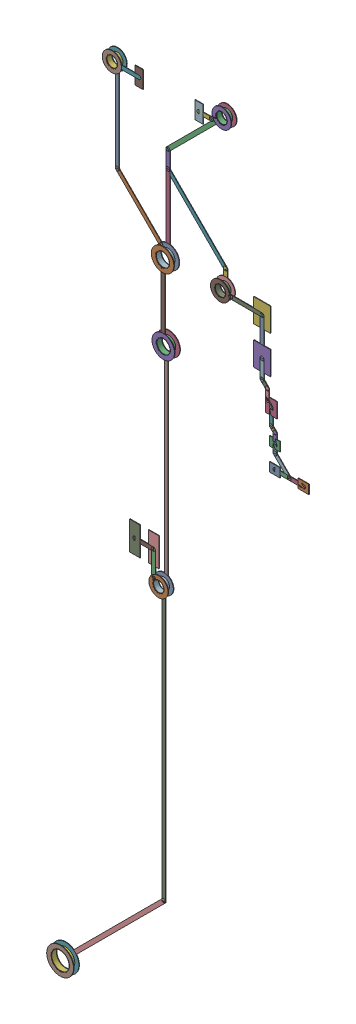
SolidWorks assembly 3V3, configuration Predeterminado. Lengths in mm.
Overall size (17.43 55.45 0.39).
184 component instances, 51 part files, 0 mates.
Components (placement in the parent):
- Track (17.2mm,51.761mm)(17.2mm,58.1mm) on Bottom Layer-1: Track (17.2mm,51.761mm)(17.2mm,58.1mm) on Bottom Layer [Predeterminado] at origin size (0.25 6.13 0.04)
  - Track (17.2mm,51.761mm)(17.2mm,58.1mm) on Bottom Layer-1-1: Track (17.2mm,51.761mm)(17.2mm,58.1mm) on Bottom Layer-1 [Predeterminado] at (-68.317 -44.187 -0.4013) size (0.25 6.13 0.04)
    - Track (17.2mm,51.761mm)(17.2mm,58.1mm) on Bottom Layer-Part-1-1: Track (17.2mm,51.761mm)(17.2mm,58.1mm) on Bottom Layer-Part-1 [Predeterminado] at origin size (0.25 6.13 0.04)
- Track (17.2mm,51.761mm)(20.574mm,48.387mm) on Bottom Layer-1: Track (17.2mm,51.761mm)(20.574mm,48.387mm) on Bottom Layer [Predeterminado] at origin size (3.29 3.29 0.04)
  - Track (17.2mm,51.761mm)(20.574mm,48.387mm) on Bottom Layer-1-1: Track (17.2mm,51.761mm)(20.574mm,48.387mm) on Bottom Layer-1 [Predeterminado] at (-68.317 -44.187 -0.4013) size (3.29 3.29 0.04)
    - Track (17.2mm,51.761mm)(20.574mm,48.387mm) on Bottom Layer-Part-1-1: Track (17.2mm,51.761mm)(20.574mm,48.387mm) on Bottom Layer-Part-1 [Predeterminado] at origin size (3.29 3.29 0.04)
- Track (20.574mm,54.574mm)(24.5mm,58.5mm) on Bottom Layer-1: Track (20.574mm,54.574mm)(24.5mm,58.5mm) on Bottom Layer [Predeterminado] at origin size (3.91 3.91 0.04)
  - Track (20.574mm,54.574mm)(24.5mm,58.5mm) on Bottom Layer-1-1: Track (20.574mm,54.574mm)(24.5mm,58.5mm) on Bottom Layer-1 [Predeterminado] at (-68.317 -44.187 -0.4013) size (3.91 3.91 0.04)
    - Track (20.574mm,54.574mm)(24.5mm,58.5mm) on Bottom Layer-Part-1-1: Track (20.574mm,54.574mm)(24.5mm,58.5mm) on Bottom Layer-Part-1 [Predeterminado] at origin size (3.91 3.91 0.04)
- Track (20.574mm,48.387mm)(20.574mm,53.426mm) on Bottom Layer-1: Track (20.574mm,48.387mm)(20.574mm,53.426mm) on Bottom Layer [Predeterminado] at origin size (0.25 4.73 0.04)
  - Track (20.574mm,48.387mm)(20.574mm,53.426mm) on Bottom Layer-1-1: Track (20.574mm,48.387mm)(20.574mm,53.426mm) on Bottom Layer-1 [Predeterminado] at (-68.317 -44.187 -0.4013) size (0.25 4.73 0.04)
    - Track (20.574mm,48.387mm)(20.574mm,53.426mm) on Bottom Layer-Part-1-1: Track (20.574mm,48.387mm)(20.574mm,53.426mm) on Bottom Layer-Part-1 [Predeterminado] at origin size (0.25 4.73 0.04)
- Track (20.574mm,53.426mm)(20.574mm,54.574mm) on Bottom Layer-1: Track (20.574mm,53.426mm)(20.574mm,54.574mm) on Bottom Layer [Predeterminado] at origin size (0.25 1.4 0.04)
  - Track (20.574mm,53.426mm)(20.574mm,54.574mm) on Bottom Layer-1-1: Track (20.574mm,53.426mm)(20.574mm,54.574mm) on Bottom Layer-1 [Predeterminado] at (-68.317 -44.187 -0.4013) size (0.25 1.4 0.04)
    - Track (20.574mm,53.426mm)(20.574mm,54.574mm) on Bottom Layer-Part-1-1: Track (20.574mm,53.426mm)(20.574mm,54.574mm) on Bottom Layer-Part-1 [Predeterminado] at origin size (0.25 1.4 0.04)
- Track (24.4mm,48.5mm)(24.4mm,49.6mm) on Bottom Layer-1: Track (24.4mm,48.5mm)(24.4mm,49.6mm) on Bottom Layer [Predeterminado] at origin size (0.25 0.89 0.04)
  - Track (24.4mm,48.5mm)(24.4mm,49.6mm) on Bottom Layer-1-1: Track (24.4mm,48.5mm)(24.4mm,49.6mm) on Bottom Layer-1 [Predeterminado] at (-68.317 -44.187 -0.4013) size (0.25 0.89 0.04)
    - Track (24.4mm,48.5mm)(24.4mm,49.6mm) on Bottom Layer-Part-1-1: Track (24.4mm,48.5mm)(24.4mm,49.6mm) on Bottom Layer-Part-1 [Predeterminado] at origin size (0.25 0.89 0.04)
- Track (20.574mm,53.426mm)(24.4mm,49.6mm) on Bottom Layer-1: Track (20.574mm,53.426mm)(24.4mm,49.6mm) on Bottom Layer [Predeterminado] at origin size (4.08 4.08 0.04)
  - Track (20.574mm,53.426mm)(24.4mm,49.6mm) on Bottom Layer-1-1: Track (20.574mm,53.426mm)(24.4mm,49.6mm) on Bottom Layer-1 [Predeterminado] at (-68.317 -44.187 -0.4013) size (4.08 4.08 0.04)
    - Track (20.574mm,53.426mm)(24.4mm,49.6mm) on Bottom Layer-Part-1-1: Track (20.574mm,53.426mm)(24.4mm,49.6mm) on Bottom Layer-Part-1 [Predeterminado] at origin size (4.08 4.08 0.04)
- Track (20.46mm,29.56mm)(20.46mm,43.24mm) on Bottom Layer-1: Track (20.46mm,29.56mm)(20.46mm,43.24mm) on Bottom Layer [Predeterminado] at origin size (0.25 13.44 0.04)
  - Track (20.46mm,29.56mm)(20.46mm,43.24mm) on Bottom Layer-1-1: Track (20.46mm,29.56mm)(20.46mm,43.24mm) on Bottom Layer-1 [Predeterminado] at (-68.317 -44.187 -0.4013) size (0.25 13.44 0.04)
    - Track (20.46mm,29.56mm)(20.46mm,43.24mm) on Bottom Layer-Part-1-1: Track (20.46mm,29.56mm)(20.46mm,43.24mm) on Bottom Layer-Part-1 [Predeterminado] at origin size (0.25 13.44 0.04)
- Track (20.3mm,11.119mm)(20.3mm,29.4mm) on Bottom Layer-1: Track (20.3mm,11.119mm)(20.3mm,29.4mm) on Bottom Layer [Predeterminado] at origin size (0.25 18.08 0.04)
  - Track (20.3mm,11.119mm)(20.3mm,29.4mm) on Bottom Layer-1-1: Track (20.3mm,11.119mm)(20.3mm,29.4mm) on Bottom Layer-1 [Predeterminado] at (-68.317 -44.187 -0.4013) size (0.25 18.08 0.04)
    - Track (20.3mm,11.119mm)(20.3mm,29.4mm) on Bottom Layer-Part-1-1: Track (20.3mm,11.119mm)(20.3mm,29.4mm) on Bottom Layer-Part-1 [Predeterminado] at origin size (0.25 18.08 0.04)
- Track (13.758mm,4.578mm)(20.3mm,11.119mm) on Bottom Layer-1: Track (13.758mm,4.578mm)(20.3mm,11.119mm) on Bottom Layer [Predeterminado] at origin size (6.35 6.35 0.04)
  - Track (13.758mm,4.578mm)(20.3mm,11.119mm) on Bottom Layer-1-1: Track (13.758mm,4.578mm)(20.3mm,11.119mm) on Bottom Layer-1 [Predeterminado] at (-68.317 -44.187 -0.4013) size (6.35 6.35 0.04)
    - Track (13.758mm,4.578mm)(20.3mm,11.119mm) on Bottom Layer-Part-1-1: Track (13.758mm,4.578mm)(20.3mm,11.119mm) on Bottom Layer-Part-1 [Predeterminado] at origin size (6.35 6.35 0.04)
- Track (20.597mm,43.423mm)(20.597mm,48.364mm) on Top Layer-1: Track (20.597mm,43.423mm)(20.597mm,48.364mm) on Top Layer [Predeterminado] at origin size (0.25 4.14 0.04)
  - Track (20.597mm,43.423mm)(20.597mm,48.364mm) on Top Layer-1-1: Track (20.597mm,43.423mm)(20.597mm,48.364mm) on Top Layer-1 [Predeterminado] at (-68.317 -44.187 -0.0457) size (0.25 4.14 0.04)
    - Track (20.597mm,43.423mm)(20.597mm,48.364mm) on Top Layer-Part-1-1: Track (20.597mm,43.423mm)(20.597mm,48.364mm) on Top Layer-Part-1 [Predeterminado] at origin size (0.25 4.14 0.04)
- Track (28.05mm,40.95mm)(29mm,40mm) on Top Layer-1: Track (28.05mm,40.95mm)(29mm,40mm) on Top Layer [Predeterminado] at origin size (1.2 1.2 0.04)
  - Track (28.05mm,40.95mm)(29mm,40mm) on Top Layer-1-1: Track (28.05mm,40.95mm)(29mm,40mm) on Top Layer-1 [Predeterminado] at (-68.317 -44.187 -0.0457) size (1.2 1.2 0.04)
    - Track (28.05mm,40.95mm)(29mm,40mm) on Top Layer-Part-1-1: Track (28.05mm,40.95mm)(29mm,40mm) on Top Layer-Part-1 [Predeterminado] at origin size (1.2 1.2 0.04)
- Track (28.05mm,40.95mm)(28.05mm,41.5mm) on Top Layer-1: Track (28.05mm,40.95mm)(28.05mm,41.5mm) on Top Layer [Predeterminado] at origin size (0.25 0.8 0.04)
  - Track (28.05mm,40.95mm)(28.05mm,41.5mm) on Top Layer-1-1: Track (28.05mm,40.95mm)(28.05mm,41.5mm) on Top Layer-1 [Predeterminado] at (-68.317 -44.187 -0.0457) size (0.25 0.8 0.04)
    - Track (28.05mm,40.95mm)(28.05mm,41.5mm) on Top Layer-Part-1-1: Track (28.05mm,40.95mm)(28.05mm,41.5mm) on Top Layer-Part-1 [Predeterminado] at origin size (0.25 0.8 0.04)
- Track (29mm,40mm)(29mm,40mm) on Top Layer-1: Track (29mm,40mm)(29mm,40mm) on Top Layer [Predeterminado] at origin size (0.25 0.25 0.04)
  - Track (29mm,40mm)(29mm,40mm) on Top Layer-1-1: Track (29mm,40mm)(29mm,40mm) on Top Layer-1 [Predeterminado] at (-68.317 -44.187 -0.0457) size (0.25 0.25 0.04)
    - Track (29mm,40mm)(29mm,40mm) on Top Layer-Part-1-1: Track (29mm,40mm)(29mm,40mm) on Top Layer-Part-1 [Predeterminado] at origin size (0.25 0.25 0.04)
- Track (28.05mm,40mm)(29mm,40mm) on Top Layer-1: Track (28.05mm,40mm)(29mm,40mm) on Top Layer [Predeterminado] at origin size (1.2 0.25 0.04)
  - Track (28.05mm,40mm)(29mm,40mm) on Top Layer-1-1: Track (28.05mm,40mm)(29mm,40mm) on Top Layer-1 [Predeterminado] at (-68.317 -44.187 -0.0457) size (1.2 0.25 0.04)
    - Track (28.05mm,40mm)(29mm,40mm) on Top Layer-Part-1-1: Track (28.05mm,40mm)(29mm,40mm) on Top Layer-Part-1 [Predeterminado] at origin size (1.2 0.25 0.04)
- Track (29mm,40mm)(29.95mm,40mm) on Top Layer-1: Track (29mm,40mm)(29.95mm,40mm) on Top Layer [Predeterminado] at origin size (1.2 0.25 0.04)
  - Track (29mm,40mm)(29.95mm,40mm) on Top Layer-1-1: Track (29mm,40mm)(29.95mm,40mm) on Top Layer-1 [Predeterminado] at (-68.317 -44.187 -0.0457) size (1.2 0.25 0.04)
    - Track (29mm,40mm)(29.95mm,40mm) on Top Layer-Part-1-1: Track (29mm,40mm)(29.95mm,40mm) on Top Layer-Part-1 [Predeterminado] at origin size (1.2 0.25 0.04)
- Track (28.05mm,41.5mm)(28.05mm,42.15mm) on Top Layer-1: Track (28.05mm,41.5mm)(28.05mm,42.15mm) on Top Layer [Predeterminado] at origin size (0.25 0.9 0.04)
  - Track (28.05mm,41.5mm)(28.05mm,42.15mm) on Top Layer-1-1: Track (28.05mm,41.5mm)(28.05mm,42.15mm) on Top Layer-1 [Predeterminado] at (-68.317 -44.187 -0.0457) size (0.25 0.9 0.04)
    - Track (28.05mm,41.5mm)(28.05mm,42.15mm) on Top Layer-Part-1-1: Track (28.05mm,41.5mm)(28.05mm,42.15mm) on Top Layer-Part-1 [Predeterminado] at origin size (0.25 0.9 0.04)
- Track (27.8mm,42.4mm)(28.05mm,42.15mm) on Top Layer-1: Track (27.8mm,42.4mm)(28.05mm,42.15mm) on Top Layer [Predeterminado] at origin size (0.5 0.5 0.04)
  - Track (27.8mm,42.4mm)(28.05mm,42.15mm) on Top Layer-1-1: Track (27.8mm,42.4mm)(28.05mm,42.15mm) on Top Layer-1 [Predeterminado] at (-68.317 -44.187 -0.0457) size (0.5 0.5 0.04)
    - Track (27.8mm,42.4mm)(28.05mm,42.15mm) on Top Layer-Part-1-1: Track (27.8mm,42.4mm)(28.05mm,42.15mm) on Top Layer-Part-1 [Predeterminado] at origin size (0.5 0.5 0.04)
- Track (27.8mm,42.4mm)(27.8mm,43.5mm) on Top Layer-1: Track (27.8mm,42.4mm)(27.8mm,43.5mm) on Top Layer [Predeterminado] at origin size (0.25 1.35 0.04)
  - Track (27.8mm,42.4mm)(27.8mm,43.5mm) on Top Layer-1-1: Track (27.8mm,42.4mm)(27.8mm,43.5mm) on Top Layer-1 [Predeterminado] at (-68.317 -44.187 -0.0457) size (0.25 1.35 0.04)
    - Track (27.8mm,42.4mm)(27.8mm,43.5mm) on Top Layer-Part-1-1: Track (27.8mm,42.4mm)(27.8mm,43.5mm) on Top Layer-Part-1 [Predeterminado] at origin size (0.25 1.35 0.04)
- Track (27.8mm,43.5mm)(27.8mm,43.5mm) on Top Layer-1: Track (27.8mm,43.5mm)(27.8mm,43.5mm) on Top Layer [Predeterminado] at origin size (0.25 0.25 0.04)
  - Track (27.8mm,43.5mm)(27.8mm,43.5mm) on Top Layer-1-1: Track (27.8mm,43.5mm)(27.8mm,43.5mm) on Top Layer-1 [Predeterminado] at (-68.317 -44.187 -0.0457) size (0.25 0.25 0.04)
    - Track (27.8mm,43.5mm)(27.8mm,43.5mm) on Top Layer-Part-1-1: Track (27.8mm,43.5mm)(27.8mm,43.5mm) on Top Layer-Part-1 [Predeterminado] at origin size (0.25 0.25 0.04)
- Track (27.19mm,44.778mm)(27.537mm,44.431mm) on Top Layer-1: Track (27.19mm,44.778mm)(27.537mm,44.431mm) on Top Layer [Predeterminado] at origin size (0.6 0.6 0.04)
  - Track (27.19mm,44.778mm)(27.537mm,44.431mm) on Top Layer-1-1: Track (27.19mm,44.778mm)(27.537mm,44.431mm) on Top Layer-1 [Predeterminado] at (-68.317 -44.187 -0.0457) size (0.6 0.6 0.04)
    - Track (27.19mm,44.778mm)(27.537mm,44.431mm) on Top Layer-Part-1-1: Track (27.19mm,44.778mm)(27.537mm,44.431mm) on Top Layer-Part-1 [Predeterminado] at origin size (0.6 0.6 0.04)
- Track (27.537mm,43.763mm)(27.537mm,44.431mm) on Top Layer-1: Track (27.537mm,43.763mm)(27.537mm,44.431mm) on Top Layer [Predeterminado] at origin size (0.25 0.92 0.04)
  - Track (27.537mm,43.763mm)(27.537mm,44.431mm) on Top Layer-1-1: Track (27.537mm,43.763mm)(27.537mm,44.431mm) on Top Layer-1 [Predeterminado] at (-68.317 -44.187 -0.0457) size (0.25 0.92 0.04)
    - Track (27.537mm,43.763mm)(27.537mm,44.431mm) on Top Layer-Part-1-1: Track (27.537mm,43.763mm)(27.537mm,44.431mm) on Top Layer-Part-1 [Predeterminado] at origin size (0.25 0.92 0.04)
- Track (27.537mm,43.763mm)(27.8mm,43.5mm) on Top Layer-1: Track (27.537mm,43.763mm)(27.8mm,43.5mm) on Top Layer [Predeterminado] at origin size (0.52 0.52 0.04)
  - Track (27.537mm,43.763mm)(27.8mm,43.5mm) on Top Layer-1-1: Track (27.537mm,43.763mm)(27.8mm,43.5mm) on Top Layer-1 [Predeterminado] at (-68.317 -44.187 -0.0457) size (0.52 0.52 0.04)
    - Track (27.537mm,43.763mm)(27.8mm,43.5mm) on Top Layer-Part-1-1: Track (27.537mm,43.763mm)(27.8mm,43.5mm) on Top Layer-Part-1 [Predeterminado] at origin size (0.52 0.52 0.04)
- Track (27.19mm,44.778mm)(27.19mm,46mm) on Top Layer-1: Track (27.19mm,44.778mm)(27.19mm,46mm) on Top Layer [Predeterminado] at origin size (0.25 1.48 0.04)
  - Track (27.19mm,44.778mm)(27.19mm,46mm) on Top Layer-1-1: Track (27.19mm,44.778mm)(27.19mm,46mm) on Top Layer-1 [Predeterminado] at (-68.317 -44.187 -0.0457) size (0.25 1.48 0.04)
    - Track (27.19mm,44.778mm)(27.19mm,46mm) on Top Layer-Part-1-1: Track (27.19mm,44.778mm)(27.19mm,46mm) on Top Layer-Part-1 [Predeterminado] at origin size (0.25 1.48 0.04)
- Track (27.19mm,46mm)(27.19mm,48.5mm) on Top Layer-1: Track (27.19mm,46mm)(27.19mm,48.5mm) on Top Layer [Predeterminado] at origin size (0.25 2.75 0.04)
  - Track (27.19mm,46mm)(27.19mm,48.5mm) on Top Layer-1-1: Track (27.19mm,46mm)(27.19mm,48.5mm) on Top Layer-1 [Predeterminado] at (-68.317 -44.187 -0.0457) size (0.25 2.75 0.04)
    - Track (27.19mm,46mm)(27.19mm,48.5mm) on Top Layer-Part-1-1: Track (27.19mm,46mm)(27.19mm,48.5mm) on Top Layer-Part-1 [Predeterminado] at origin size (0.25 2.75 0.04)
- Track (19.975mm,29.725mm)(20.3mm,29.4mm) on Top Layer-1: Track (19.975mm,29.725mm)(20.3mm,29.4mm) on Top Layer [Predeterminado] at origin size (0.31 0.31 0.04)
  - Track (19.975mm,29.725mm)(20.3mm,29.4mm) on Top Layer-1-1: Track (19.975mm,29.725mm)(20.3mm,29.4mm) on Top Layer-1 [Predeterminado] at (-68.317 -44.187 -0.0457) size (0.31 0.31 0.04)
    - Track (19.975mm,29.725mm)(20.3mm,29.4mm) on Top Layer-Part-1-1: Track (19.975mm,29.725mm)(20.3mm,29.4mm) on Top Layer-Part-1 [Predeterminado] at origin size (0.31 0.31 0.04)
- Track (19.975mm,29.725mm)(19.975mm,31.391mm) on Top Layer-1: Track (19.975mm,29.725mm)(19.975mm,31.391mm) on Top Layer [Predeterminado] at origin size (0.25 1.92 0.04)
  - Track (19.975mm,29.725mm)(19.975mm,31.391mm) on Top Layer-1-1: Track (19.975mm,29.725mm)(19.975mm,31.391mm) on Top Layer-1 [Predeterminado] at (-68.317 -44.187 -0.0457) size (0.25 1.92 0.04)
    - Track (19.975mm,29.725mm)(19.975mm,31.391mm) on Top Layer-Part-1-1: Track (19.975mm,29.725mm)(19.975mm,31.391mm) on Top Layer-Part-1 [Predeterminado] at origin size (0.25 1.92 0.04)
- Track (24.225mm,58.5mm)(24.5mm,58.5mm) on Top Layer-1: Track (24.225mm,58.5mm)(24.5mm,58.5mm) on Top Layer [Predeterminado] at origin size (0.06 0.22 0.04)
  - Track (24.225mm,58.5mm)(24.5mm,58.5mm) on Top Layer-1-1: Track (24.225mm,58.5mm)(24.5mm,58.5mm) on Top Layer-1 [Predeterminado] at (-68.317 -44.187 -0.0457) size (0.06 0.22 0.04)
    - Track (24.225mm,58.5mm)(24.5mm,58.5mm) on Top Layer-Part-1-1: Track (24.225mm,58.5mm)(24.5mm,58.5mm) on Top Layer-Part-1 [Predeterminado] at origin size (0.06 0.22 0.04)
- Track (23.822mm,58.097mm)(24.225mm,58.5mm) on Top Layer-1: Track (23.822mm,58.097mm)(24.225mm,58.5mm) on Top Layer [Predeterminado] at origin size (0.51 0.64 0.04)
  - Track (23.822mm,58.097mm)(24.225mm,58.5mm) on Top Layer-1-1: Track (23.822mm,58.097mm)(24.225mm,58.5mm) on Top Layer-1 [Predeterminado] at (-68.317 -44.187 -0.0457) size (0.51 0.64 0.04)
    - Track (23.822mm,58.097mm)(24.225mm,58.5mm) on Top Layer-Part-1-1: Track (23.822mm,58.097mm)(24.225mm,58.5mm) on Top Layer-Part-1 [Predeterminado] at origin size (0.51 0.64 0.04)
- Track (23mm,58.097mm)(23.822mm,58.097mm) on Top Layer-1: Track (23mm,58.097mm)(23.822mm,58.097mm) on Top Layer [Predeterminado] at origin size (1.08 0.25 0.04)
  - Track (23mm,58.097mm)(23.822mm,58.097mm) on Top Layer-1-1: Track (23mm,58.097mm)(23.822mm,58.097mm) on Top Layer-1 [Predeterminado] at (-68.317 -44.187 -0.0457) size (1.08 0.25 0.04)
    - Track (23mm,58.097mm)(23.822mm,58.097mm) on Top Layer-Part-1-1: Track (23mm,58.097mm)(23.822mm,58.097mm) on Top Layer-Part-1 [Predeterminado] at origin size (1.08 0.25 0.04)
- Track (17.203mm,58.097mm)(19mm,58.097mm) on Top Layer-1: Track (17.203mm,58.097mm)(19mm,58.097mm) on Top Layer [Predeterminado] at origin size (1.6 0.25 0.04)
  - Track (17.203mm,58.097mm)(19mm,58.097mm) on Top Layer-1-1: Track (17.203mm,58.097mm)(19mm,58.097mm) on Top Layer-1 [Predeterminado] at (-68.317 -44.187 -0.0457) size (1.6 0.25 0.04)
    - Track (17.203mm,58.097mm)(19mm,58.097mm) on Top Layer-Part-1-1: Track (17.203mm,58.097mm)(19mm,58.097mm) on Top Layer-Part-1 [Predeterminado] at origin size (1.6 0.25 0.04)
- Track (25.1mm,48.5mm)(25.1mm,48.5mm) on Top Layer-1: Track (25.1mm,48.5mm)(25.1mm,48.5mm) on Top Layer [Predeterminado] at origin size (0.25 0.25 0.04)
  - Track (25.1mm,48.5mm)(25.1mm,48.5mm) on Top Layer-1-1: Track (25.1mm,48.5mm)(25.1mm,48.5mm) on Top Layer-1 [Predeterminado] at (-68.317 -44.187 -0.0457) size (0.25 0.25 0.04)
    - Track (25.1mm,48.5mm)(25.1mm,48.5mm) on Top Layer-Part-1-1: Track (25.1mm,48.5mm)(25.1mm,48.5mm) on Top Layer-Part-1 [Predeterminado] at origin size (0.25 0.25 0.04)
- Track (25.1mm,48.5mm)(27.19mm,48.5mm) on Top Layer-1: Track (25.1mm,48.5mm)(27.19mm,48.5mm) on Top Layer [Predeterminado] at origin size (2.34 0.25 0.04)
  - Track (25.1mm,48.5mm)(27.19mm,48.5mm) on Top Layer-1-1: Track (25.1mm,48.5mm)(27.19mm,48.5mm) on Top Layer-1 [Predeterminado] at (-68.317 -44.187 -0.0457) size (2.34 0.25 0.04)
    - Track (25.1mm,48.5mm)(27.19mm,48.5mm) on Top Layer-Part-1-1: Track (25.1mm,48.5mm)(27.19mm,48.5mm) on Top Layer-Part-1 [Predeterminado] at origin size (2.34 0.25 0.04)
- Track (24.4mm,48.5mm)(25.1mm,48.5mm) on Top Layer-1: Track (24.4mm,48.5mm)(25.1mm,48.5mm) on Top Layer [Predeterminado] at origin size (0.49 0.25 0.04)
  - Track (24.4mm,48.5mm)(25.1mm,48.5mm) on Top Layer-1-1: Track (24.4mm,48.5mm)(25.1mm,48.5mm) on Top Layer-1 [Predeterminado] at (-68.317 -44.187 -0.0457) size (0.49 0.25 0.04)
    - Track (24.4mm,48.5mm)(25.1mm,48.5mm) on Top Layer-Part-1-1: Track (24.4mm,48.5mm)(25.1mm,48.5mm) on Top Layer-Part-1 [Predeterminado] at origin size (0.49 0.25 0.04)
- Track (18.725mm,31.391mm)(19.975mm,31.391mm) on Top Layer-1: Track (18.725mm,31.391mm)(19.975mm,31.391mm) on Top Layer [Predeterminado] at origin size (1.5 0.25 0.04)
  - Track (18.725mm,31.391mm)(19.975mm,31.391mm) on Top Layer-1-1: Track (18.725mm,31.391mm)(19.975mm,31.391mm) on Top Layer-1 [Predeterminado] at (-68.317 -44.187 -0.0457) size (1.5 0.25 0.04)
    - Track (18.725mm,31.391mm)(19.975mm,31.391mm) on Top Layer-Part-1-1: Track (18.725mm,31.391mm)(19.975mm,31.391mm) on Top Layer-Part-1 [Predeterminado] at origin size (1.5 0.25 0.04)
- Via (20.3mm,29.4mm) from Top Layer to Bottom Layer-1: Via (20.3mm,29.4mm) from Top Layer to Bottom Layer [Predeterminado] at origin size (1.27 1.27 0.39)
  - Via Hole-1: Via Hole [Predeterminado] at (20.3 29.4 -0.4013) size (0.76 0.76 0.39)
    - Via Hole-Part-1-1: Via Hole-Part-1 [Predeterminado] at origin size (0.76 0.76 0.39)
  - Via Top Layer-1: Via Top Layer [Predeterminado] at (20.3 29.4 -0.4013) size (1.27 1.27 0.04)
    - Via Top Layer-Part-1-1: Via Top Layer-Part-1 [Predeterminado] at origin size (1.27 1.27 0.04)
  - Via Top Layer-2: Via Top Layer [Predeterminado] at (20.3 29.4 -0.0457) size (1.27 1.27 0.04)
    - Via Top Layer-Part-1-1: Via Top Layer-Part-1 [Predeterminado] at origin size (1.27 1.27 0.04)
- Via (24.5mm,58.5mm) from Top Layer to Bottom Layer-1: Via (24.5mm,58.5mm) from Top Layer to Bottom Layer [Predeterminado] at origin size (1.27 1.27 0.39)
  - Via Hole-1: Via Hole [Predeterminado] at (24.5 58.5 -0.4013) size (0.76 0.76 0.39)
    - Via Hole-Part-1-1: Via Hole-Part-1 [Predeterminado] at origin size (0.76 0.76 0.39)
  - Via Top Layer-1: Via Top Layer [Predeterminado] at (24.5 58.5 -0.4013) size (1.27 1.27 0.04)
    - Via Top Layer-Part-1-1: Via Top Layer-Part-1 [Predeterminado] at origin size (1.27 1.27 0.04)
  - Via Top Layer-2: Via Top Layer [Predeterminado] at (24.5 58.5 -0.0457) size (1.27 1.27 0.04)
    - Via Top Layer-Part-1-1: Via Top Layer-Part-1 [Predeterminado] at origin size (1.27 1.27 0.04)
- Via (17.2mm,58.1mm) from Top Layer to Bottom Layer-1: Via (17.2mm,58.1mm) from Top Layer to Bottom Layer [Predeterminado] at origin size (1.27 1.27 0.39)
  - Via Hole-1: Via Hole [Predeterminado] at (17.2 58.1 -0.4013) size (0.76 0.76 0.39)
    - Via Hole-Part-1-1: Via Hole-Part-1 [Predeterminado] at origin size (0.76 0.76 0.39)
  - Via Top Layer-1: Via Top Layer [Predeterminado] at (17.2 58.1 -0.4013) size (1.27 1.27 0.04)
    - Via Top Layer-Part-1-1: Via Top Layer-Part-1 [Predeterminado] at origin size (1.27 1.27 0.04)
  - Via Top Layer-2: Via Top Layer [Predeterminado] at (17.2 58.1 -0.0457) size (1.27 1.27 0.04)
    - Via Top Layer-Part-1-1: Via Top Layer-Part-1 [Predeterminado] at origin size (1.27 1.27 0.04)
- Via (24.4mm,48.5mm) from Top Layer to Bottom Layer-1: Via (24.4mm,48.5mm) from Top Layer to Bottom Layer [Predeterminado] at origin size (1.27 1.27 0.39)
  - Via Hole-1: Via Hole [Predeterminado] at (24.4 48.5 -0.4013) size (0.76 0.76 0.39)
    - Via Hole-Part-1-1: Via Hole-Part-1 [Predeterminado] at origin size (0.76 0.76 0.39)
  - Via Top Layer-1: Via Top Layer [Predeterminado] at (24.4 48.5 -0.4013) size (1.27 1.27 0.04)
    - Via Top Layer-Part-1-1: Via Top Layer-Part-1 [Predeterminado] at origin size (1.27 1.27 0.04)
  - Via Top Layer-2: Via Top Layer [Predeterminado] at (24.4 48.5 -0.0457) size (1.27 1.27 0.04)
    - Via Top Layer-Part-1-1: Via Top Layer-Part-1 [Predeterminado] at origin size (1.27 1.27 0.04)
- Pad SWD-4(20.574mm,48.387mm) on Multi-Layer-1: Pad SWD-4(20.574mm,48.387mm) on Multi-Layer [Predeterminado] at origin size (1.5 1.5 0.39)
  - Pad Hole-1-1: Pad Hole-1 [Predeterminado] at (20.574 48.387 -0.4013) size (0.95 0.95 0.39)
    - Pad Hole-Part-1-1-1: Pad Hole-Part-1-1 [Predeterminado] at origin size (0.95 0.95 0.39)
  - Top Layer-1-1: Top Layer-1 [Predeterminado] at (20.574 48.387 -0.4013) size (1.5 1.5 0.04)
    - Top Layer-Part-1-1-1: Top Layer-Part-1-1 [Predeterminado] at origin size (1.5 1.5 0.04)
  - Top Layer-1-2: Top Layer-1 [Predeterminado] at (20.574 48.387 -0.0457) size (1.5 1.5 0.04)
    - Top Layer-Part-1-1-1: Top Layer-Part-1-1 [Predeterminado] at origin size (1.5 1.5 0.04)
- Pad UART-4(20.62mm,43.4mm) on Multi-Layer-1: Pad UART-4(20.62mm,43.4mm) on Multi-Layer [Predeterminado] at origin size (1.5 1.5 0.39)
  - Pad Hole-1-1: Pad Hole-1 [Predeterminado] at (20.62 43.4 -0.4013) size (0.95 0.95 0.39)
    - Pad Hole-Part-1-1-1: Pad Hole-Part-1-1 [Predeterminado] at origin size (0.95 0.95 0.39)
  - Top Layer-1-1: Top Layer-1 [Predeterminado] at (20.62 43.4 -0.4013) size (1.5 1.5 0.04)
    - Top Layer-Part-1-1-1: Top Layer-Part-1-1 [Predeterminado] at origin size (1.5 1.5 0.04)
  - Top Layer-1-2: Top Layer-1 [Predeterminado] at (20.62 43.4 -0.0457) size (1.5 1.5 0.04)
    - Top Layer-Part-1-1-1: Top Layer-Part-1-1 [Predeterminado] at origin size (1.5 1.5 0.04)
- Pad U1-4(13.758mm,4.578mm) on Multi-Layer-1: Pad U1-4(13.758mm,4.578mm) on Multi-Layer [Predeterminado] at origin size (1.79 1.79 0.39)
  - Pad Hole-1: Pad Hole [Predeterminado] at (13.7584 4.5777 -0.4013) size (1.24 1.24 0.39)
    - Pad Hole-Part-1-1: Pad Hole-Part-1 [Predeterminado] at origin size (1.24 1.24 0.39)
  - Top Layer-1: Top Layer [Predeterminado] at (13.7584 4.5777 -0.4013) size (1.79 1.79 0.04)
    - Top Layer-Part-1-1: Top Layer-Part-1 [Predeterminado] at origin size (1.79 1.79 0.04)
  - Top Layer-2: Top Layer [Predeterminado] at (13.7584 4.5777 -0.0457) size (1.79 1.79 0.04)
    - Top Layer-Part-1-1: Top Layer-Part-1 [Predeterminado] at origin size (1.79 1.79 0.04)
- Pad RAK4600-41(18.725mm,31.391mm) on Top Layer-1: Pad RAK4600-41(18.725mm,31.391mm) on Top Layer [Predeterminado] at origin size (0.7 1.9 0.04)
  - Pad RAK4600-41(18.725mm,31.391mm) on Top Layer-1-1: Pad RAK4600-41(18.725mm,31.391mm) on Top Layer-1 [Predeterminado] at (-68.317 -44.187 -0.0457) size (0.7 1.9 0.04)
    - Pad RAK4600-41(18.725mm,31.391mm) on Top Layer-Part-1-1: Pad RAK4600-41(18.725mm,31.391mm) on Top Layer-Part-1 [Predeterminado] at origin size (0.7 1.9 0.04)
- Pad RAK4600-40(19.975mm,31.391mm) on Top Layer-1: Pad RAK4600-40(19.975mm,31.391mm) on Top Layer [Predeterminado] at origin size (0.7 1.9 0.04)
  - Pad RAK4600-40(19.975mm,31.391mm) on Top Layer-1-1: Pad RAK4600-40(19.975mm,31.391mm) on Top Layer-1 [Predeterminado] at (-68.317 -44.187 -0.0457) size (0.7 1.9 0.04)
    - Pad RAK4600-40(19.975mm,31.391mm) on Top Layer-Part-1-1: Pad RAK4600-40(19.975mm,31.391mm) on Top Layer-Part-1 [Predeterminado] at origin size (0.7 1.9 0.04)
- Pad ADXL345-6(19mm,58.097mm) on Top Layer-1: Pad ADXL345-6(19mm,58.097mm) on Top Layer [Predeterminado] at origin size (0.55 1.15 0.04)
  - Pad ADXL345-6(19mm,58.097mm) on Top Layer-1-1: Pad ADXL345-6(19mm,58.097mm) on Top Layer-1 [Predeterminado] at (-68.317 -44.187 -0.0457) size (0.55 1.15 0.04)
    - Pad ADXL345-6(19mm,58.097mm) on Top Layer-Part-1-1: Pad ADXL345-6(19mm,58.097mm) on Top Layer-Part-1 [Predeterminado] at origin size (0.55 1.15 0.04)
- Pad ADXL345-1(23mm,58.097mm) on Top Layer-1: Pad ADXL345-1(23mm,58.097mm) on Top Layer [Predeterminado] at origin size (0.55 1.15 0.04)
  - Pad ADXL345-1(23mm,58.097mm) on Top Layer-1-1: Pad ADXL345-1(23mm,58.097mm) on Top Layer-1 [Predeterminado] at (-68.317 -44.187 -0.0457) size (0.55 1.15 0.04)
    - Pad ADXL345-1(23mm,58.097mm) on Top Layer-Part-1-1: Pad ADXL345-1(23mm,58.097mm) on Top Layer-Part-1 [Predeterminado] at origin size (0.55 1.15 0.04)
- Pad R1-2(28.05mm,40mm) on Top Layer-1: Pad R1-2(28.05mm,40mm) on Top Layer [Predeterminado] at origin size (0.7 0.6 0.04)
  - Pad R1-2(28.05mm,40mm) on Top Layer-1-1: Pad R1-2(28.05mm,40mm) on Top Layer-1 [Predeterminado] at (-68.317 -44.187 -0.0457) size (0.7 0.6 0.04)
    - Pad R1-2(28.05mm,40mm) on Top Layer-Part-1-1: Pad R1-2(28.05mm,40mm) on Top Layer-Part-1 [Predeterminado] at origin size (0.7 0.6 0.04)
- Pad R2-2(29.95mm,40mm) on Top Layer-1: Pad R2-2(29.95mm,40mm) on Top Layer [Predeterminado] at origin size (0.7 0.6 0.04)
  - Pad R2-2(29.95mm,40mm) on Top Layer-1-1: Pad R2-2(29.95mm,40mm) on Top Layer-1 [Predeterminado] at (-68.317 -44.187 -0.0457) size (0.7 0.6 0.04)
    - Pad R2-2(29.95mm,40mm) on Top Layer-Part-1-1: Pad R2-2(29.95mm,40mm) on Top Layer-Part-1 [Predeterminado] at origin size (0.7 0.6 0.04)
- Pad R4-1(28.05mm,41.5mm) on Top Layer-1: Pad R4-1(28.05mm,41.5mm) on Top Layer [Predeterminado] at origin size (0.7 0.6 0.04)
  - Pad R4-1(28.05mm,41.5mm) on Top Layer-1-1: Pad R4-1(28.05mm,41.5mm) on Top Layer-1 [Predeterminado] at (-68.317 -44.187 -0.0457) size (0.7 0.6 0.04)
    - Pad R4-1(28.05mm,41.5mm) on Top Layer-Part-1-1: Pad R4-1(28.05mm,41.5mm) on Top Layer-Part-1 [Predeterminado] at origin size (0.7 0.6 0.04)
- Pad C2-2(27.8mm,43.5mm) on Top Layer-1: Pad C2-2(27.8mm,43.5mm) on Top Layer [Predeterminado] at origin size (0.78 0.99 0.04)
  - Pad C2-2(27.8mm,43.5mm) on Top Layer-1-1: Pad C2-2(27.8mm,43.5mm) on Top Layer-1 [Predeterminado] at (-68.317 -44.187 -0.0457) size (0.78 0.99 0.04)
    - Pad C2-2(27.8mm,43.5mm) on Top Layer-Part-1-1: Pad C2-2(27.8mm,43.5mm) on Top Layer-Part-1 [Predeterminado] at origin size (0.78 0.99 0.04)
- Pad C1-2(27.19mm,46mm) on Top Layer-1: Pad C1-2(27.19mm,46mm) on Top Layer [Predeterminado] at origin size (1.1 1.57 0.04)
  - Pad C1-2(27.19mm,46mm) on Top Layer-1-1: Pad C1-2(27.19mm,46mm) on Top Layer-1 [Predeterminado] at (-68.317 -44.187 -0.0457) size (1.1 1.57 0.04)
    - Pad C1-2(27.19mm,46mm) on Top Layer-Part-1-1: Pad C1-2(27.19mm,46mm) on Top Layer-Part-1 [Predeterminado] at origin size (1.1 1.57 0.04)
- Pad C3-2(27.19mm,48.5mm) on Top Layer-1: Pad C3-2(27.19mm,48.5mm) on Top Layer [Predeterminado] at origin size (1.1 1.57 0.04)
  - Pad C3-2(27.19mm,48.5mm) on Top Layer-1-1: Pad C3-2(27.19mm,48.5mm) on Top Layer-1 [Predeterminado] at (-68.317 -44.187 -0.0457) size (1.1 1.57 0.04)
    - Pad C3-2(27.19mm,48.5mm) on Top Layer-Part-1-1: Pad C3-2(27.19mm,48.5mm) on Top Layer-Part-1 [Predeterminado] at origin size (1.1 1.57 0.04)
